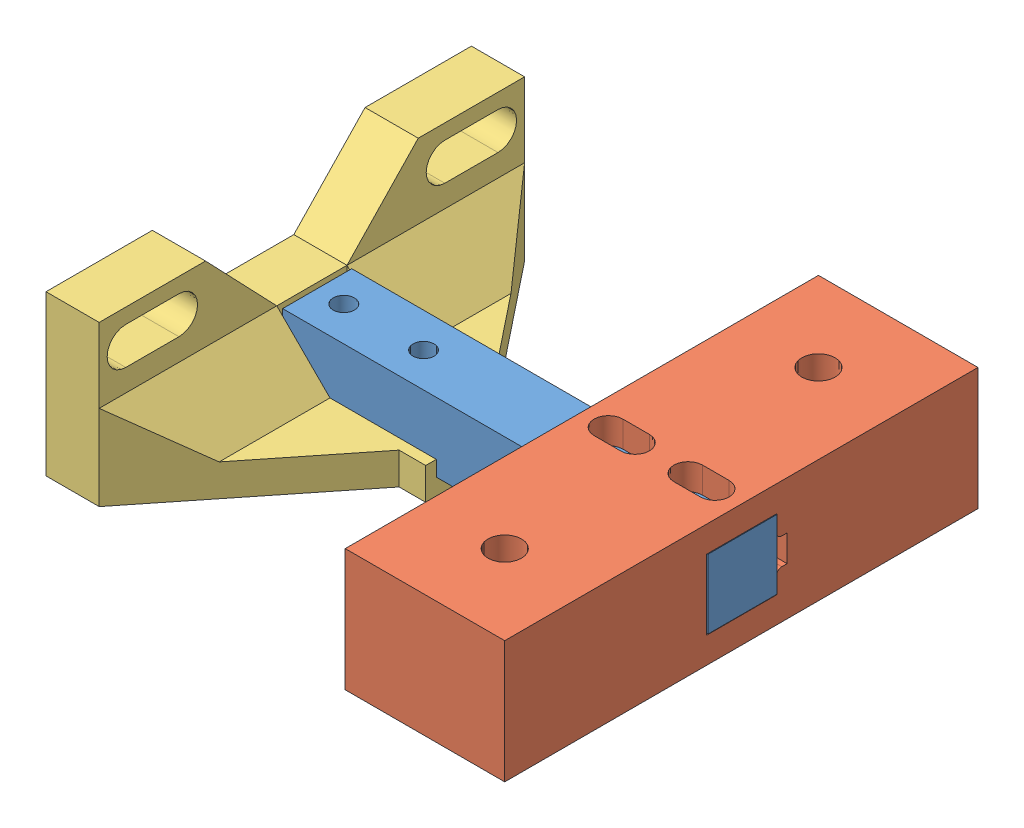
SolidWorks assembly Assemblage1, configuration Défaut. Lengths in mm.
Overall size (91 32.1 89).
3 component instances, 3 part files, 5 mates.
Components (placement in the parent):
- loadcell-1: loadcell [Défaut] at (-1.1865 -1.9847 8) size (80 13 13)
- base-1: base [Défaut] at (74.2284 4.4376 54.99) x (0 0 -1) z (0 -1 0) size (89 30 23)
- clamp-1: clamp [Défaut] at (7.9541 -13.4624 14.9379) x (0 0 1) z (0 -1 0) size (80 40 30)
Mates (geometry in assembly coordinates):
- Coïncidente1: coincident: plane of loadcell-1 through (-3.7291 -0.4624 21) normal (0 1 0); plane of base-1 through (46.1373 -0.4624 54.99) normal (0 -1 0)
- Coïncidente2: coincident: plane of loadcell-1 through (-1.1865 -1.9847 8) normal (0 0 -1); plane of base-1 through (46.1373 4.4376 8) normal (0 0 1)
- Coïncidente3: coincident: plane of loadcell-1 through (-3.7291 -13.4624 21) normal (0 -1 0); plane of clamp-1 through (16.7088 -13.4624 22.8168) normal (0 1 0)
- Coaxiale1: concentric: circle of loadcell-1; cylinder of clamp-1 through (16.2709 -16.4624 14.5) axis (0 1 0) radius 2.65
- Coaxiale2: concentric: circle of loadcell-1; circle of clamp-1
